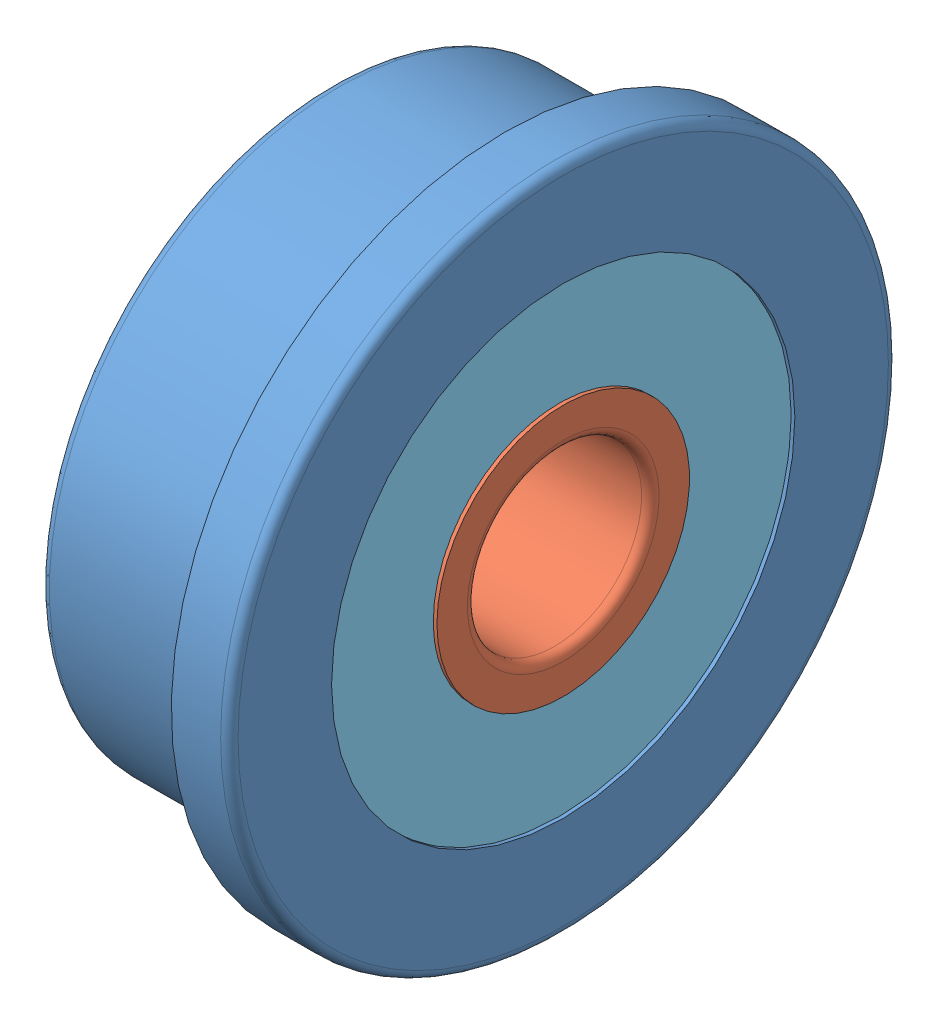
SolidWorks assembly F623ZZ v2.step, configuration Default. Lengths in mm.
Overall size (4 11.5 11.5).
11 component instances, 5 part files, 0 mates.
Components (placement in the parent):
- F623ZZ Outer Ring.step-1: F623ZZ Outer Ring.step [Default] at origin size (4 11.5 11.5)
- F623ZZ Inner Ring.step-1: F623ZZ Inner Ring.step [Default] x (1 0 0) z (0 -1 0) size (4 4.8 4.8)
- F623ZZ Shield1.step-1: F623ZZ Shield1.step [Default] at (0.5 0 0) x (-1 0 0) z (0 -1 0) size (0.19 7.98 7.98)
- F623ZZ Ball.step-1: F623ZZ Ball.step [Default] at (2 0 3.25) x (1 0 0) z (0 -1 0) size (2.1 2.1 2.1)
- F623ZZ Ball.step-2: F623ZZ Ball.step [Default] at (2 -2.541 2.0263) x (1 0 0) z (0 -1 0) size (2.1 2.1 2.1)
- F623ZZ Ball.step-3: F623ZZ Ball.step [Default] at (2 -3.1685 -0.7232) x (1 0 0) z (0 -1 0) size (2.1 2.1 2.1)
- F623ZZ Ball.step-4: F623ZZ Ball.step [Default] at (2 -1.4101 -2.9281) x (1 0 0) z (0 -1 0) size (2.1 2.1 2.1)
- F623ZZ Ball.step-5: F623ZZ Ball.step [Default] at (2 1.4101 -2.9281) x (1 0 0) z (0 -1 0) size (2.1 2.1 2.1)
- F623ZZ Ball.step-6: F623ZZ Ball.step [Default] at (2 3.1685 -0.7232) x (1 0 0) z (0 -1 0) size (2.1 2.1 2.1)
- F623ZZ Ball.step-7: F623ZZ Ball.step [Default] at (2 2.541 2.0263) x (1 0 0) z (0 -1 0) size (2.1 2.1 2.1)
- F623ZZ Shield2.step-1: F623ZZ Shield2.step [Default] at origin size (0.19 7.98 7.98)
